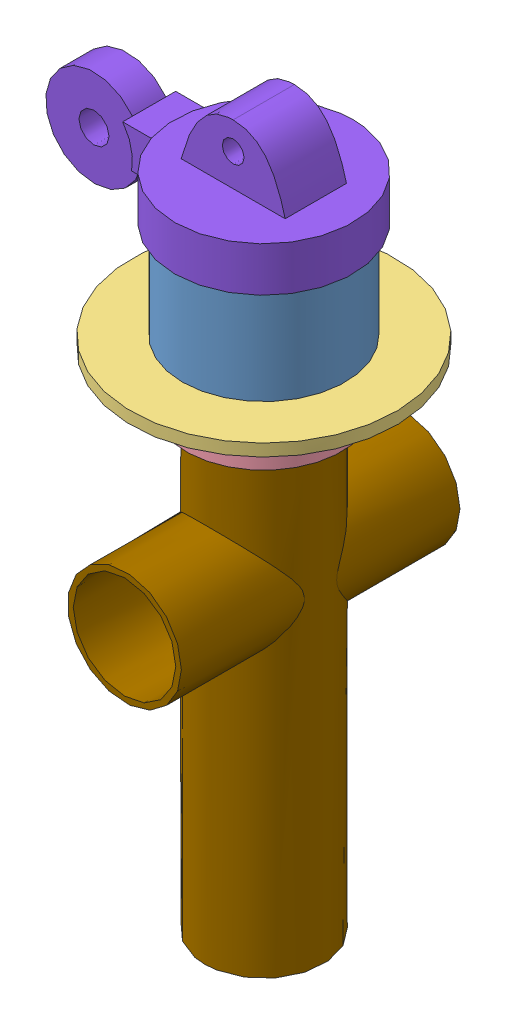
SolidWorks assembly center piece assem, configuration Default. Lengths in mm.
Overall size (134.25 257.4 123.94).
12 component instances, 9 part files, 20 mates.
Components (placement in the parent):
- center support top section-1: center support top section [Default] at (96.2621 126.254 0) size (58.48 40 58.48)
- steppo motor-1: steppo motor [Default] at (96.2621 88.254 0) x (0.379391 0 -0.925236) z (-0.925236 0 -0.379391) size (42.44 58.07 42.44)
- center piece circle wide central ring-1: center piece circle wide central ring [Default] at (96.2621 83.914 0) x (-0.379391 0 0.925236) z (-0.925236 0 -0.379391) size (95 4.34 95)
- center piece gear support-1: center piece gear support [Default] at (96.2621 51.914 0) x (-0.695714 0 -0.718319) z (0.718319 0 -0.695714) size (55.78 28 55.78)
- steppo motor screw-1: steppo motor screw [Default] at (87.7742 83.914 -20.287) x (0.961179 0 0.275927) z (0.275927 0 -0.961179) size (5.5 7.62 5.5)
- steppo motor screw-2: steppo motor screw [Default] at (75.9752 83.914 8.4879) x (0.275927 0 -0.961179) z (-0.961179 0 -0.275927) size (5.5 7.62 5.5)
- steppo motor screw-3: steppo motor screw [Default] at (104.75 83.914 20.287) x (-0.961179 0 -0.275927) z (-0.275927 0 0.961179) size (5.5 7.62 5.5)
- steppo motor screw-4: steppo motor screw [Default] at (116.5491 83.914 -8.4879) x (-0.275927 0 0.961179) z (0.961179 0 0.275927) size (5.5 7.62 5.5)
- center support ball bearign brace-1: center support ball bearign brace [Default] at (96.2621 83.914 0) x (-0.925236 0 -0.379391) z (0.379391 0 -0.925236) size (55.78 10 55.78)
- center support ball bearign brace top-1: center support ball bearign brace top [Default] at (96.2621 74.914 0) x (-0.922511 0 0.385971) z (-0.385971 0 -0.922511) size (55.78 12 55.78)
- center piece top hing part-1: center piece top hing part [Default] at (96.2621 123.254 0) x (-1 0 0) z (0 0 -1) size (104.29 49.7 64.01)
- center support v2-2: center support v2 [Default] at (96.2621 -96.7337 0) size (42.4 158.65 100)
Mates (geometry in assembly coordinates):
- Concentric2: concentric anti-aligned: cylinder of steppo motor-1 through (96.2621 86.254 0) axis (0 1 0) radius 11; cylinder of center piece circle wide central ring-1 through (96.2621 88.254 0) axis (0 -1 0) radius 11
- Concentric3: concentric aligned: cylinder of steppo motor-1 through (104.75 92.254 20.287) axis (0 -1 0) radius 1.5; cylinder of center piece circle wide central ring-1 through (104.75 88.254 20.287) axis (0 -1 0) radius 1.5
- Coincident1: coincident anti-aligned: plane of steppo motor-1 through (96.2621 88.254 0) normal (0 -1 0); plane of center piece circle wide central ring-1 through (96.2621 88.254 0) normal (0 1 0)
- Concentric4: concentric aligned: cylinder of center piece circle wide central ring-1 through (96.2621 88.254 0) axis (0 -1 0) radius 47.5; cylinder of center piece gear support-1 through (96.2621 71.914 0) axis (0 -1 0) radius 27.8896
- Concentric5: concentric anti-aligned: cylinder of steppo motor-1 through (87.7742 92.254 -20.287) axis (0 -1 0) radius 1.5; cylinder of steppo motor screw-1 through (87.7742 82.414 -20.287) axis (0 1 0) radius 2.75
- Coincident2: coincident anti-aligned: plane of center piece circle wide central ring-1 through (96.2621 83.914 0) normal (0 -1 0); plane of steppo motor screw-1 through (87.7742 83.914 -20.287) normal (0 1 0)
- Concentric6: concentric anti-aligned: cylinder of center piece circle wide central ring-1 through (96.2621 88.254 0) axis (0 -1 0) radius 11; cylinder of center support ball bearign brace-1 through (96.2621 80.914 0) axis (0 1 0) radius 27.8896
- Concentric7: concentric anti-aligned: cylinder of steppo motor-1 through (87.7742 92.254 -20.287) axis (0 -1 0) radius 1.5; cylinder of center support ball bearign brace-1 through (87.7742 80.914 -20.287) axis (0 1 0) radius 3.25
- Concentric9: concentric anti-aligned: cylinder of center support ball bearign brace-1 through (101.4249 77.914 -12.5906) axis (0.379391 0 -0.925236) radius 1.5; cylinder of center support ball bearign brace top-1 through (111.2266 77.914 -36.4944) axis (-0.379391 0 0.925236) radius 1.5
- Concentric10: concentric anti-aligned: cylinder of center support ball bearign brace-1 through (96.2621 80.914 0) axis (0 1 0) radius 3.5; cylinder of center support ball bearign brace top-1 through (96.2621 80.914 0) axis (0 -1 0) radius 8.1781
- Coincident3: coincident anti-aligned: plane of center piece circle wide central ring-1 through (96.2621 83.914 0) normal (0 -1 0); plane of center support ball bearign brace-1 through (96.2621 83.914 0) normal (0 1 0)
- Concentric11: concentric anti-aligned: cylinder of center support top section-1 through (96.2621 86.254 0) axis (0 1 0) radius 29.2395; cylinder of center piece circle wide central ring-1 through (96.2621 88.254 0) axis (0 -1 0) radius 47.5
- Coincident4: coincident anti-aligned: plane of center support top section-1 through (96.2621 86.254 0) normal (0 -1 0); plane of center piece circle wide central ring-1 through (96.2621 86.254 0) normal (0 1 0)
- Coincident5: coincident anti-aligned: plane of center piece gear support-1 through (96.2621 71.914 0) normal (0 1 0); plane of center support ball bearign brace top-1 through (96.2621 71.914 0) normal (0 -1 0)
- Concentric13: concentric anti-aligned: cylinder of center support top section-1 through (96.2621 86.254 0) axis (0 1 0) radius 29.2395; cylinder of center piece top hing part-1 through (96.2621 139.254 0) axis (0 -1 0) radius 32.0075
- Coincident7: coincident anti-aligned: plane of center support top section-1 through (96.2621 126.254 0) normal (0 1 0); plane of center piece top hing part-1 through (96.2621 126.254 0) normal (0 -1 0)
- Coincident8: coincident anti-aligned: plane of center support top section-1 through (96.2621 126.254 0) normal (0 0 1); plane of center piece top hing part-1 through (96.2621 123.254 0) normal (0 0 -1)
- Concentric15: concentric aligned: cylinder of center piece gear support-1 through (96.2621 61.914 0) axis (0 -1 0) radius 19.0099; cylinder of center support v2-2 through (96.2621 83.914 0) axis (0 -1 0) radius 19.1979
- Coincident11: coincident anti-aligned: plane of center piece gear support-1 through (96.2621 61.914 0) normal (0 -1 0); plane of center support v2-2 through (96.2621 61.914 0) normal (0 1 0)
- Coincident12: coincident aligned: plane of center support top section-1 through (96.2621 126.254 0) normal (0 0 1); plane of assembly through (0 0 0) normal (0 0 1)
